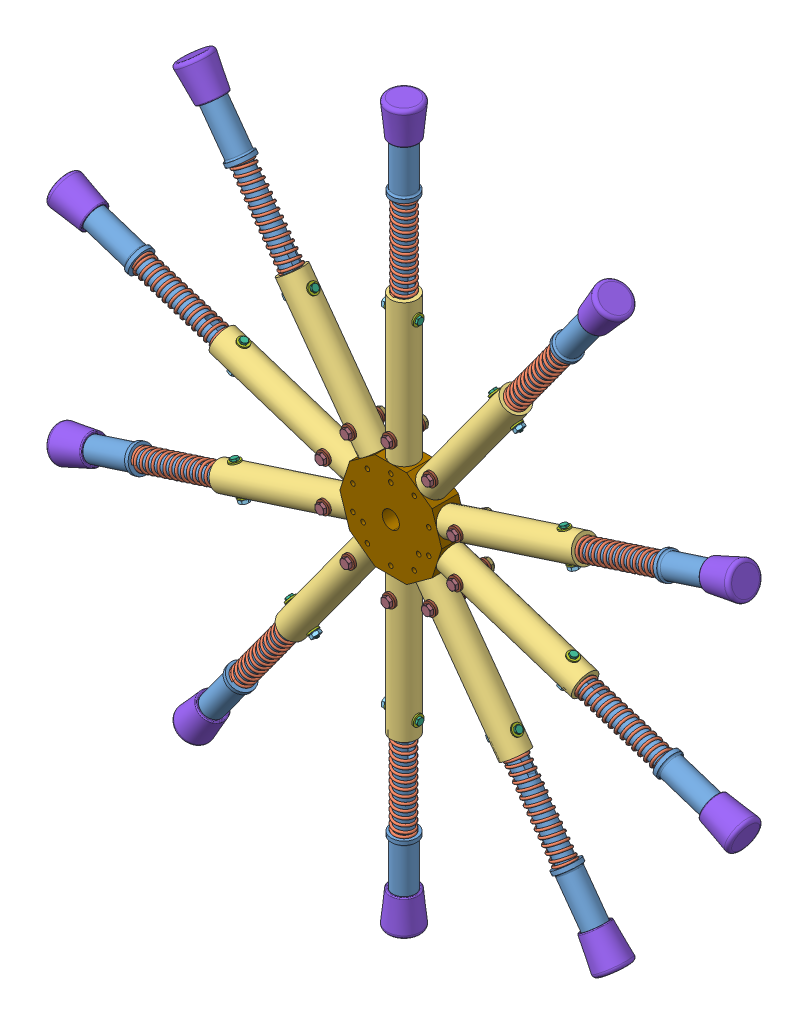
SolidWorks assembly RR2 Rimless Wheel Subassembly, configuration Default. Lengths in mm.
Overall size (516.27 533.18 29.42).
152 component instances, 13 part files, 91 mates.
Components (placement in the parent):
- RR2 Leg Subassembly-1: RR2 Leg Subassembly [Default] at (-53.9197 131.5696 42.2256) x (0 0 1) z (-0.951057 0.309017 0) size (29.42 28.7 230.63)
  - RR2 Leg Rod-1: RR2 Leg Rod [Default] at (-32.4466 0 163.322) x (-1 0 0) z (0 -1 0) size (19.05 163.32 19.05)
  - RR2 Spring-1: RR2 Spring [9657K421] at (-32.6702 -0.1472 114.3) size (17.2 17.2 64.41)
  - RR2 Leg Tube-1: RR2 Leg Tube [Default] at (-32.4466 0 50.8) x (0 -1 0) z (1 0 0) size (19.56 105.41 19.56)
  - RR2 4 Bushing-1: RR2 4 Bushing [94639A664] at (-32.4466 -0.0931 38.1) x (0.887003 0 -0.461764) z (0 1 0) size (4.76 4.76 19.05)
  - RR2 4 Nut-2: RR2 4 Nut [90101A004] at (-32.4466 -13.6074 38.1) x (0.996652 0 0.081761) z (-0.081761 0 0.996652) size (6.35 2.86 7.33)
  - RR2 4 Screw-1: RR2 4 Screw [92314A115] at (-32.4466 10.8477 38.1) x (0.159771 0 0.987154) z (0 1 0) size (4.76 5.5 27.24)
  - RR2 4 Washer-1: RR2 4 Washer [96659A101] at (-32.4466 -10.8293 38.1) x (0.112204 0 0.993685) z (-0.993685 0 0.112204) size (7.92 1.02 7.92)
  - RR2 4 Washer-2: RR2 4 Washer [96659A101] at (-32.4466 9.8317 38.1) x (-0.013346 0 0.999911) z (-0.999911 0 -0.013346) size (7.92 1.02 7.92)
  - RR2 Boot-1: RR2 Boot [Default] at (-32.4466 0 176.022) x (1 0 0) z (0 1 0) size (29.42 25.4 27.68)
- RR2 Leg Subassembly-2: RR2 Leg Subassembly [Default] at (-21.0184 176.8545 42.2256) x (0 0 1) z (-0.587785 0.809017 0) size (29.42 28.7 230.63)
  - RR2 Leg Rod-1: RR2 Leg Rod [Default] at (-32.4466 0 163.322) x (-1 0 0) z (0 -1 0) size (19.05 163.32 19.05)
  - RR2 Spring-1: RR2 Spring [9657K421] at (-32.6702 -0.1472 114.3) size (17.2 17.2 64.41)
  - RR2 Leg Tube-1: RR2 Leg Tube [Default] at (-32.4466 0 50.8) x (0 -1 0) z (1 0 0) size (19.56 105.41 19.56)
  - RR2 4 Bushing-1: RR2 4 Bushing [94639A664] at (-32.4466 -0.0931 38.1) x (0.887003 0 -0.461764) z (0 1 0) size (4.76 4.76 19.05)
  - RR2 4 Nut-2: RR2 4 Nut [90101A004] at (-32.4466 -13.6074 38.1) x (0.996652 0 0.081761) z (-0.081761 0 0.996652) size (6.35 2.86 7.33)
  - RR2 4 Screw-1: RR2 4 Screw [92314A115] at (-32.4466 10.8477 38.1) x (0.159771 0 0.987154) z (0 1 0) size (4.76 5.5 27.24)
  - RR2 4 Washer-1: RR2 4 Washer [96659A101] at (-32.4466 -10.8293 38.1) x (0.112204 0 0.993685) z (-0.993685 0 0.112204) size (7.92 1.02 7.92)
  - RR2 4 Washer-2: RR2 4 Washer [96659A101] at (-32.4466 9.8317 38.1) x (-0.013346 0 0.999911) z (-0.999911 0 -0.013346) size (7.92 1.02 7.92)
  - RR2 Boot-1: RR2 Boot [Default] at (-32.4466 0 176.022) x (1 0 0) z (0 1 0) size (29.42 25.4 27.68)
- RR2 Leg Subassembly-3: RR2 Leg Subassembly [Default] at (-21.0184 30.3097 42.2256) x (0 0 1) z (-0.587785 -0.809017 0) size (29.42 28.7 230.63)
  - RR2 Leg Rod-1: RR2 Leg Rod [Default] at (-32.4466 0 163.322) x (-1 0 0) z (0 -1 0) size (19.05 163.32 19.05)
  - RR2 Spring-1: RR2 Spring [9657K421] at (-32.6702 -0.1472 114.3) size (17.2 17.2 64.41)
  - RR2 Leg Tube-1: RR2 Leg Tube [Default] at (-32.4466 0 50.8) x (0 -1 0) z (1 0 0) size (19.56 105.41 19.56)
  - RR2 4 Bushing-1: RR2 4 Bushing [94639A664] at (-32.4466 -0.0931 38.1) x (0.887003 0 -0.461764) z (0 1 0) size (4.76 4.76 19.05)
  - RR2 4 Nut-2: RR2 4 Nut [90101A004] at (-32.4466 -13.6074 38.1) x (0.996652 0 0.081761) z (-0.081761 0 0.996652) size (6.35 2.86 7.33)
  - RR2 4 Screw-1: RR2 4 Screw [92314A115] at (-32.4466 10.8477 38.1) x (0.159771 0 0.987154) z (0 1 0) size (4.76 5.5 27.24)
  - RR2 4 Washer-1: RR2 4 Washer [96659A101] at (-32.4466 -10.8293 38.1) x (0.112204 0 0.993685) z (-0.993685 0 0.112204) size (7.92 1.02 7.92)
  - RR2 4 Washer-2: RR2 4 Washer [96659A101] at (-32.4466 9.8317 38.1) x (-0.013346 0 0.999911) z (-0.999911 0 -0.013346) size (7.92 1.02 7.92)
  - RR2 Boot-1: RR2 Boot [Default] at (-32.4466 0 176.022) x (1 0 0) z (0 1 0) size (29.42 25.4 27.68)
- RR2 Leg Subassembly-4: RR2 Leg Subassembly [Default] at (-53.9197 75.5945 42.2256) x (0 0 1) z (-0.951057 -0.309017 0) size (29.42 28.7 230.63)
  - RR2 Leg Rod-1: RR2 Leg Rod [Default] at (-32.4466 0 163.322) x (-1 0 0) z (0 -1 0) size (19.05 163.32 19.05)
  - RR2 Spring-1: RR2 Spring [9657K421] at (-32.6702 -0.1472 114.3) size (17.2 17.2 64.41)
  - RR2 Leg Tube-1: RR2 Leg Tube [Default] at (-32.4466 0 50.8) x (0 -1 0) z (1 0 0) size (19.56 105.41 19.56)
  - RR2 4 Bushing-1: RR2 4 Bushing [94639A664] at (-32.4466 -0.0931 38.1) x (0.887003 0 -0.461764) z (0 1 0) size (4.76 4.76 19.05)
  - RR2 4 Nut-2: RR2 4 Nut [90101A004] at (-32.4466 -13.6074 38.1) x (0.996652 0 0.081761) z (-0.081761 0 0.996652) size (6.35 2.86 7.33)
  - RR2 4 Screw-1: RR2 4 Screw [92314A115] at (-32.4466 10.8477 38.1) x (0.159771 0 0.987154) z (0 1 0) size (4.76 5.5 27.24)
  - RR2 4 Washer-1: RR2 4 Washer [96659A101] at (-32.4466 -10.8293 38.1) x (0.112204 0 0.993685) z (-0.993685 0 0.112204) size (7.92 1.02 7.92)
  - RR2 4 Washer-2: RR2 4 Washer [96659A101] at (-32.4466 9.8317 38.1) x (-0.013346 0 0.999911) z (-0.999911 0 -0.013346) size (7.92 1.02 7.92)
  - RR2 Boot-1: RR2 Boot [Default] at (-32.4466 0 176.022) x (1 0 0) z (0 1 0) size (29.42 25.4 27.68)
- RR2 Leg Subassembly-5: RR2 Leg Subassembly [Default] at (32.2171 194.1517 42.2256) x (0 0 1) z (0 1 0) size (29.42 28.7 230.63)
  - RR2 Leg Rod-1: RR2 Leg Rod [Default] at (-32.4466 0 163.322) x (-1 0 0) z (0 -1 0) size (19.05 163.32 19.05)
  - RR2 Spring-1: RR2 Spring [9657K421] at (-32.6702 -0.1472 114.3) size (17.2 17.2 64.41)
  - RR2 Leg Tube-1: RR2 Leg Tube [Default] at (-32.4466 0 50.8) x (0 -1 0) z (1 0 0) size (19.56 105.41 19.56)
  - RR2 4 Bushing-1: RR2 4 Bushing [94639A664] at (-32.4466 -0.0931 38.1) x (0.887003 0 -0.461764) z (0 1 0) size (4.76 4.76 19.05)
  - RR2 4 Nut-2: RR2 4 Nut [90101A004] at (-32.4466 -13.6074 38.1) x (0.996652 0 0.081761) z (-0.081761 0 0.996652) size (6.35 2.86 7.33)
  - RR2 4 Screw-1: RR2 4 Screw [92314A115] at (-32.4466 10.8477 38.1) x (0.159771 0 0.987154) z (0 1 0) size (4.76 5.5 27.24)
  - RR2 4 Washer-1: RR2 4 Washer [96659A101] at (-32.4466 -10.8293 38.1) x (0.112204 0 0.993685) z (-0.993685 0 0.112204) size (7.92 1.02 7.92)
  - RR2 4 Washer-2: RR2 4 Washer [96659A101] at (-32.4466 9.8317 38.1) x (-0.013346 0 0.999911) z (-0.999911 0 -0.013346) size (7.92 1.02 7.92)
  - RR2 Boot-1: RR2 Boot [Default] at (-32.4466 0 176.022) x (1 0 0) z (0 1 0) size (29.42 25.4 27.68)
- RR2 Leg Subassembly-6: RR2 Leg Subassembly [Default] at (85.4526 176.8545 -22.6676) x (0 0 -1) z (0.587785 0.809017 0) size (29.42 28.7 230.63)
  - RR2 Leg Rod-1: RR2 Leg Rod [Default] at (-32.4466 0 163.322) x (-1 0 0) z (0 -1 0) size (19.05 163.32 19.05)
  - RR2 Spring-1: RR2 Spring [9657K421] at (-32.6702 -0.1472 114.3) size (17.2 17.2 64.41)
  - RR2 Leg Tube-1: RR2 Leg Tube [Default] at (-32.4466 0 50.8) x (0 -1 0) z (1 0 0) size (19.56 105.41 19.56)
  - RR2 4 Bushing-1: RR2 4 Bushing [94639A664] at (-32.4466 -0.0931 38.1) x (0.887003 0 -0.461764) z (0 1 0) size (4.76 4.76 19.05)
  - RR2 4 Nut-2: RR2 4 Nut [90101A004] at (-32.4466 -13.6074 38.1) x (0.996652 0 0.081761) z (-0.081761 0 0.996652) size (6.35 2.86 7.33)
  - RR2 4 Screw-1: RR2 4 Screw [92314A115] at (-32.4466 10.8477 38.1) x (0.159771 0 0.987154) z (0 1 0) size (4.76 5.5 27.24)
  - RR2 4 Washer-1: RR2 4 Washer [96659A101] at (-32.4466 -10.8293 38.1) x (0.112204 0 0.993685) z (-0.993685 0 0.112204) size (7.92 1.02 7.92)
  - RR2 4 Washer-2: RR2 4 Washer [96659A101] at (-32.4466 9.8317 38.1) x (-0.013346 0 0.999911) z (-0.999911 0 -0.013346) size (7.92 1.02 7.92)
  - RR2 Boot-1: RR2 Boot [Default] at (-32.4466 0 176.022) x (1 0 0) z (0 1 0) size (29.42 25.4 27.68)
- RR2 Leg Subassembly-7: RR2 Leg Subassembly [Default] at (118.354 131.5696 -22.6676) x (0 0 -1) z (0.951057 0.309017 0) size (29.42 28.7 230.63)
  - RR2 Leg Rod-1: RR2 Leg Rod [Default] at (-32.4466 0 163.322) x (-1 0 0) z (0 -1 0) size (19.05 163.32 19.05)
  - RR2 Spring-1: RR2 Spring [9657K421] at (-32.6702 -0.1472 114.3) size (17.2 17.2 64.41)
  - RR2 Leg Tube-1: RR2 Leg Tube [Default] at (-32.4466 0 50.8) x (0 -1 0) z (1 0 0) size (19.56 105.41 19.56)
  - RR2 4 Bushing-1: RR2 4 Bushing [94639A664] at (-32.4466 -0.0931 38.1) x (0.887003 0 -0.461764) z (0 1 0) size (4.76 4.76 19.05)
  - RR2 4 Nut-2: RR2 4 Nut [90101A004] at (-32.4466 -13.6074 38.1) x (0.996652 0 0.081761) z (-0.081761 0 0.996652) size (6.35 2.86 7.33)
  - RR2 4 Screw-1: RR2 4 Screw [92314A115] at (-32.4466 10.8477 38.1) x (0.159771 0 0.987154) z (0 1 0) size (4.76 5.5 27.24)
  - RR2 4 Washer-1: RR2 4 Washer [96659A101] at (-32.4466 -10.8293 38.1) x (0.112204 0 0.993685) z (-0.993685 0 0.112204) size (7.92 1.02 7.92)
  - RR2 4 Washer-2: RR2 4 Washer [96659A101] at (-32.4466 9.8317 38.1) x (-0.013346 0 0.999911) z (-0.999911 0 -0.013346) size (7.92 1.02 7.92)
  - RR2 Boot-1: RR2 Boot [Default] at (-32.4466 0 176.022) x (1 0 0) z (0 1 0) size (29.42 25.4 27.68)
- RR2 Leg Subassembly-8: RR2 Leg Subassembly [Default] at (118.354 75.5945 -22.6676) x (0 0 -1) z (0.951057 -0.309017 0) size (29.42 28.7 230.63)
  - RR2 Leg Rod-1: RR2 Leg Rod [Default] at (-32.4466 0 163.322) x (-1 0 0) z (0 -1 0) size (19.05 163.32 19.05)
  - RR2 Spring-1: RR2 Spring [9657K421] at (-32.6702 -0.1472 114.3) size (17.2 17.2 64.41)
  - RR2 Leg Tube-1: RR2 Leg Tube [Default] at (-32.4466 0 50.8) x (0 -1 0) z (1 0 0) size (19.56 105.41 19.56)
  - RR2 4 Bushing-1: RR2 4 Bushing [94639A664] at (-32.4466 -0.0931 38.1) x (0.887003 0 -0.461764) z (0 1 0) size (4.76 4.76 19.05)
  - RR2 4 Nut-2: RR2 4 Nut [90101A004] at (-32.4466 -13.6074 38.1) x (0.996652 0 0.081761) z (-0.081761 0 0.996652) size (6.35 2.86 7.33)
  - RR2 4 Screw-1: RR2 4 Screw [92314A115] at (-32.4466 10.8477 38.1) x (0.159771 0 0.987154) z (0 1 0) size (4.76 5.5 27.24)
  - RR2 4 Washer-1: RR2 4 Washer [96659A101] at (-32.4466 -10.8293 38.1) x (0.112204 0 0.993685) z (-0.993685 0 0.112204) size (7.92 1.02 7.92)
  - RR2 4 Washer-2: RR2 4 Washer [96659A101] at (-32.4466 9.8317 38.1) x (-0.013346 0 0.999911) z (-0.999911 0 -0.013346) size (7.92 1.02 7.92)
  - RR2 Boot-1: RR2 Boot [Default] at (-32.4466 0 176.022) x (1 0 0) z (0 1 0) size (29.42 25.4 27.68)
- RR2 Leg Subassembly-9: RR2 Leg Subassembly [Default] at (85.4526 30.3097 -22.6676) x (0 0 -1) z (0.587785 -0.809017 0) size (29.42 28.7 230.63)
  - RR2 Leg Rod-1: RR2 Leg Rod [Default] at (-32.4466 0 163.322) x (-1 0 0) z (0 -1 0) size (19.05 163.32 19.05)
  - RR2 Spring-1: RR2 Spring [9657K421] at (-32.6702 -0.1472 114.3) size (17.2 17.2 64.41)
  - RR2 Leg Tube-1: RR2 Leg Tube [Default] at (-32.4466 0 50.8) x (0 -1 0) z (1 0 0) size (19.56 105.41 19.56)
  - RR2 4 Bushing-1: RR2 4 Bushing [94639A664] at (-32.4466 -0.0931 38.1) x (0.887003 0 -0.461764) z (0 1 0) size (4.76 4.76 19.05)
  - RR2 4 Nut-2: RR2 4 Nut [90101A004] at (-32.4466 -13.6074 38.1) x (0.996652 0 0.081761) z (-0.081761 0 0.996652) size (6.35 2.86 7.33)
  - RR2 4 Screw-1: RR2 4 Screw [92314A115] at (-32.4466 10.8477 38.1) x (0.159771 0 0.987154) z (0 1 0) size (4.76 5.5 27.24)
  - RR2 4 Washer-1: RR2 4 Washer [96659A101] at (-32.4466 -10.8293 38.1) x (0.112204 0 0.993685) z (-0.993685 0 0.112204) size (7.92 1.02 7.92)
  - RR2 4 Washer-2: RR2 4 Washer [96659A101] at (-32.4466 9.8317 38.1) x (-0.013346 0 0.999911) z (-0.999911 0 -0.013346) size (7.92 1.02 7.92)
  - RR2 Boot-1: RR2 Boot [Default] at (-32.4466 0 176.022) x (1 0 0) z (0 1 0) size (29.42 25.4 27.68)
- RR2 Hub Subassembly-1: RR2 Hub Subassembly [Default] at (22.7483 69.4036 0) size (125.44 128.31 19.56)
  - RR2 Hub Rev B-1: RR2 Hub Rev B [Default] at (9.4688 34.1785 19.558) size (75.62 71.92 19.56)
  - RR2 Peg-1: RR2 Peg [Default] at (23.1405 52.9959 9.779) x (0.809017 -0.587785 0) z (0 0 1) size (11.05 40.89 11.05)
  - RR2 Peg-2: RR2 Peg [Default] at (9.4688 57.4381 9.779) x (-1 0 0) z (0 0 -1) size (11.05 40.89 11.05)
  - RR2 Peg-3: RR2 Peg [Default] at (31.5901 26.9908 9.779) x (-0.309017 -0.951057 0) z (0 0 1) size (11.05 40.89 11.05)
  - RR2 Peg-4: RR2 Peg [Default] at (31.5901 41.3661 9.779) x (0.309017 -0.951057 0) z (0 0 1) size (11.05 40.89 11.05)
  - RR2 Peg-5: RR2 Peg [Default] at (-4.2028 52.9959 9.779) x (0.809017 0.587785 0) z (0 0 1) size (11.05 40.89 11.05)
  - RR2 Peg-6: RR2 Peg [Default] at (-12.6524 26.9908 9.779) x (-0.309017 0.951057 0) z (0 0 1) size (11.05 40.89 11.05)
  - RR2 Peg-7: RR2 Peg [Default] at (-12.6524 41.3661 9.779) x (-0.309017 -0.951057 0) z (0 0 -1) size (11.05 40.89 11.05)
  - RR2 Peg-8: RR2 Peg [Default] at (-4.2028 15.361 9.779) x (-0.809017 0.587785 0) z (0 0 1) size (11.05 40.89 11.05)
  - RR2 Peg-9: RR2 Peg [Default] at (9.4688 10.9188 9.779) x (-1 0 0) z (0 0 1) size (11.05 40.89 11.05)
  - RR2 Peg-10: RR2 Peg [Default] at (23.1405 15.361 9.779) x (0.809017 0.587785 0) z (0 0 -1) size (11.05 40.89 11.05)
- RR2 Leg Subassembly-11: RR2 Leg Subassembly [Default] at (32.2171 13.0124 -22.6676) x (0 0 -1) z (0 -1 0) size (29.42 28.7 230.63)
  - RR2 Leg Rod-1: RR2 Leg Rod [Default] at (-32.4466 0 163.322) x (-1 0 0) z (0 -1 0) size (19.05 163.32 19.05)
  - RR2 Spring-1: RR2 Spring [9657K421] at (-32.6702 -0.1472 114.3) size (17.2 17.2 64.41)
  - RR2 Leg Tube-1: RR2 Leg Tube [Default] at (-32.4466 0 50.8) x (0 -1 0) z (1 0 0) size (19.56 105.41 19.56)
  - RR2 4 Bushing-1: RR2 4 Bushing [94639A664] at (-32.4466 -0.0931 38.1) x (0.887003 0 -0.461764) z (0 1 0) size (4.76 4.76 19.05)
  - RR2 4 Nut-2: RR2 4 Nut [90101A004] at (-32.4466 -13.6074 38.1) x (0.996652 0 0.081761) z (-0.081761 0 0.996652) size (6.35 2.86 7.33)
  - RR2 4 Screw-1: RR2 4 Screw [92314A115] at (-32.4466 10.8477 38.1) x (0.159771 0 0.987154) z (0 1 0) size (4.76 5.5 27.24)
  - RR2 4 Washer-1: RR2 4 Washer [96659A101] at (-32.4466 -10.8293 38.1) x (0.112204 0 0.993685) z (-0.993685 0 0.112204) size (7.92 1.02 7.92)
  - RR2 4 Washer-2: RR2 4 Washer [96659A101] at (-32.4466 9.8317 38.1) x (-0.013346 0 0.999911) z (-0.999911 0 -0.013346) size (7.92 1.02 7.92)
  - RR2 Boot-1: RR2 Boot [Default] at (-32.4466 0 176.022) x (1 0 0) z (0 1 0) size (29.42 25.4 27.68)
- RR2 6 Washer-1: RR2 6 Washer [96659A102] at (32.2171 155.0357 19.558) x (1 0 0) z (0 -1 0) size (9.53 1.65 9.53)
- RR2 6 Washer-2: RR2 6 Washer [96659A102] at (32.2171 155.0357 -1.651) x (1 0 0) z (0 -1 0) size (9.53 1.65 9.53)
- RR2 6 Washer-3: RR2 6 Washer [96659A102] at (62.4608 145.2089 21.209) x (1 0 0) z (0 1 0) size (9.53 1.65 9.53)
- RR2 6 Washer-4: RR2 6 Washer [96659A102] at (62.4608 145.2089 -1.651) x (1 0 0) z (0 -1 0) size (9.53 1.65 9.53)
- RR2 6 Washer-5: RR2 6 Washer [96659A102] at (81.1525 119.4821 21.209) x (1 0 0) z (0 1 0) size (9.53 1.65 9.53)
- RR2 6 Washer-6: RR2 6 Washer [96659A102] at (81.1525 119.4821 -1.651) x (1 0 0) z (0 -1 0) size (9.53 1.65 9.53)
- RR2 6 Washer-7: RR2 6 Washer [96659A102] at (81.1525 87.682 21.209) x (1 0 0) z (0 1 0) size (9.53 1.65 9.53)
- RR2 6 Washer-8: RR2 6 Washer [96659A102] at (81.1525 87.682 -1.651) x (1 0 0) z (0 -1 0) size (9.53 1.65 9.53)
- RR2 6 Washer-9: RR2 6 Washer [96659A102] at (62.4608 61.9552 21.209) x (1 0 0) z (0 1 0) size (9.53 1.65 9.53)
- RR2 6 Washer-10: RR2 6 Washer [96659A102] at (62.4608 61.9552 -1.651) x (1 0 0) z (0 -1 0) size (9.53 1.65 9.53)
- RR2 6 Washer-11: RR2 6 Washer [96659A102] at (32.2171 52.1284 21.209) x (1 0 0) z (0 1 0) size (9.53 1.65 9.53)
- RR2 6 Washer-12: RR2 6 Washer [96659A102] at (32.2171 52.1284 -1.651) x (1 0 0) z (0 -1 0) size (9.53 1.65 9.53)
- RR2 6 Washer-13: RR2 6 Washer [96659A102] at (1.9734 61.9552 21.209) x (1 0 0) z (0 1 0) size (9.53 1.65 9.53)
- RR2 6 Washer-14: RR2 6 Washer [96659A102] at (1.9734 61.9552 -1.651) x (1 0 0) z (0 -1 0) size (9.53 1.65 9.53)
- RR2 6 Washer-15: RR2 6 Washer [96659A102] at (-16.7182 87.682 21.209) x (1 0 0) z (0 1 0) size (9.53 1.65 9.53)
- RR2 6 Washer-16: RR2 6 Washer [96659A102] at (-16.7182 87.682 -1.651) x (1 0 0) z (0 -1 0) size (9.53 1.65 9.53)
- RR2 6 Washer-17: RR2 6 Washer [96659A102] at (-16.7182 119.4821 21.209) x (1 0 0) z (0 1 0) size (9.53 1.65 9.53)
- RR2 6 Washer-18: RR2 6 Washer [96659A102] at (-16.7182 119.4821 -1.651) x (1 0 0) z (0 -1 0) size (9.53 1.65 9.53)
- RR2 6 Washer-19: RR2 6 Washer [96659A102] at (1.9734 145.2089 21.209) x (1 0 0) z (0 1 0) size (9.53 1.65 9.53)
- RR2 6 Washer-20: RR2 6 Washer [96659A102] at (1.9734 145.2089 -1.651) x (1 0 0) z (0 -1 0) size (9.53 1.65 9.53)
- RR2 6 Nut-1: RR2 6 Nut [90101A007] at (32.2171 155.0357 -1.651) x (1 0 0) z (0 1 0) size (7.94 3.28 9.17)
- RR2 6 Nut-2: RR2 6 Nut [90101A007] at (62.4608 145.2089 -1.651) x (1 0 0) z (0 1 0) size (7.94 3.28 9.17)
- RR2 6 Nut-3: RR2 6 Nut [90101A007] at (81.1525 119.4821 -1.651) x (1 0 0) z (0 1 0) size (7.94 3.28 9.17)
- RR2 6 Nut-4: RR2 6 Nut [90101A007] at (81.1525 87.682 -1.651) x (1 0 0) z (0 1 0) size (7.94 3.28 9.17)
- RR2 6 Nut-5: RR2 6 Nut [90101A007] at (62.4608 61.9552 -1.651) x (1 0 0) z (0 1 0) size (7.94 3.28 9.17)
- RR2 6 Nut-6: RR2 6 Nut [90101A007] at (32.2171 52.1284 -1.651) x (1 0 0) z (0 1 0) size (7.94 3.28 9.17)
- RR2 6 Nut-7: RR2 6 Nut [90101A007] at (1.9734 61.9552 -1.651) x (1 0 0) z (0 1 0) size (7.94 3.28 9.17)
- RR2 6 Nut-8: RR2 6 Nut [90101A007] at (-16.7182 87.682 -1.651) x (1 0 0) z (0 1 0) size (7.94 3.28 9.17)
- RR2 6 Nut-9: RR2 6 Nut [90101A007] at (-16.7182 119.4821 -1.651) x (1 0 0) z (0 1 0) size (7.94 3.28 9.17)
- RR2 6 Nut-10: RR2 6 Nut [90101A007] at (1.9734 145.2089 -1.651) x (1 0 0) z (0 1 0) size (7.94 3.28 9.17)
- RR2 6 Screw-1: RR2 6 Screw [92314A153] at (32.2171 155.0357 21.4758) size (6.35 7.33 28.12)
- RR2 6 Screw-2: RR2 6 Screw [92314A153] at (62.4608 145.2089 21.4758) size (6.35 7.33 28.12)
- RR2 6 Screw-3: RR2 6 Screw [92314A153] at (81.1525 119.4821 21.4758) size (6.35 7.33 28.12)
- RR2 6 Screw-4: RR2 6 Screw [92314A153] at (81.1525 87.682 21.4758) size (6.35 7.33 28.12)
- RR2 6 Screw-5: RR2 6 Screw [92314A153] at (62.4608 61.9552 21.4758) size (6.35 7.33 28.12)
- RR2 6 Screw-6: RR2 6 Screw [92314A153] at (32.2171 52.1284 21.4758) size (6.35 7.33 28.12)
- RR2 6 Screw-7: RR2 6 Screw [92314A153] at (1.9734 61.9552 21.4758) size (6.35 7.33 28.12)
- RR2 6 Screw-8: RR2 6 Screw [92314A153] at (-16.7182 87.682 21.4758) size (6.35 7.33 28.12)
- RR2 6 Screw-9: RR2 6 Screw [92314A153] at (-16.7182 119.4821 21.4758) size (6.35 7.33 28.12)
- RR2 6 Screw-10: RR2 6 Screw [92314A153] at (1.9734 145.2089 21.4758) size (6.35 7.33 28.12)
Mates (geometry in assembly coordinates):
- Coincident1: coincident anti-aligned: plane of RR2 Hub Subassembly-1/RR2 Hub Rev B-1 through (32.2171 103.5821 0) normal (0 0 -1); plane of assembly through (0 0 0) normal (0 0 1)
- Concentric1: concentric anti-aligned: cylinder of RR2 Leg Subassembly-5/RR2 Leg Tube-1 through (32.2171 139.5417 9.779) axis (0 1 0) radius 5.7785; cylinder of RR2 Hub Subassembly-1/RR2 Peg-2 through (32.2171 167.7357 9.779) axis (0 -1 0) radius 5.5245
- Concentric2: concentric anti-aligned: cylinder of RR2 Leg Subassembly-2/RR2 Leg Tube-1 through (11.0806 132.674 9.779) axis (-0.587785 0.809017 0) radius 5.7785; cylinder of RR2 Hub Subassembly-1/RR2 Peg-5 through (-5.4914 155.4835 9.779) axis (0.587785 -0.809017 0) radius 5.5245
- Concentric3: concentric anti-aligned: cylinder of RR2 Leg Subassembly-1/RR2 Leg Tube-1 through (-1.9825 114.6942 9.779) axis (-0.951057 0.309017 0) radius 5.7785; cylinder of RR2 Hub Subassembly-1/RR2 Peg-7 through (-28.7966 123.4066 9.779) axis (0.951057 -0.309017 0) radius 5.5245
- Concentric4: concentric anti-aligned: cylinder of RR2 Leg Subassembly-4/RR2 Leg Tube-1 through (-1.9825 92.4699 9.779) axis (-0.951057 -0.309017 0) radius 5.7785; cylinder of RR2 Hub Subassembly-1/RR2 Peg-6 through (-28.7966 83.7575 9.779) axis (0.951057 0.309017 0) radius 5.5245
- Concentric5: concentric anti-aligned: cylinder of RR2 Leg Subassembly-3/RR2 Leg Tube-1 through (11.0806 74.4901 9.779) axis (-0.587785 -0.809017 0) radius 5.7785; cylinder of RR2 Hub Subassembly-1/RR2 Peg-8 through (-5.4914 51.6807 9.779) axis (0.587785 0.809017 0) radius 5.5245
- Concentric6: concentric anti-aligned: cylinder of RR2 Hub Subassembly-1/RR2 Peg-9 through (32.2171 39.4284 9.779) axis (0 1 0) radius 5.5245; cylinder of RR2 Leg Subassembly-11/RR2 Leg Tube-1 through (32.2171 67.6224 9.779) axis (0 -1 0) radius 5.7785
- Concentric7: concentric anti-aligned: cylinder of RR2 Leg Subassembly-9/RR2 Leg Tube-1 through (53.3537 74.4901 9.779) axis (0.587785 -0.809017 0) radius 5.7785; cylinder of RR2 Hub Subassembly-1/RR2 Peg-10 through (69.9257 51.6807 9.779) axis (-0.587785 0.809017 0) radius 5.5245
- Concentric8: concentric anti-aligned: cylinder of RR2 Leg Subassembly-8/RR2 Leg Tube-1 through (66.4168 92.4699 9.779) axis (0.951057 -0.309017 0) radius 5.7785; cylinder of RR2 Hub Subassembly-1/RR2 Peg-3 through (93.2309 83.7575 9.779) axis (-0.951057 0.309017 0) radius 5.5245
- Concentric9: concentric anti-aligned: cylinder of RR2 Leg Subassembly-7/RR2 Leg Tube-1 through (66.4168 114.6942 9.779) axis (0.951057 0.309017 0) radius 5.7785; cylinder of RR2 Hub Subassembly-1/RR2 Peg-4 through (93.2309 123.4066 9.779) axis (-0.951057 -0.309017 0) radius 5.5245
- Concentric10: concentric anti-aligned: cylinder of RR2 Leg Subassembly-6/RR2 Leg Tube-1 through (53.3537 132.674 9.779) axis (0.587785 0.809017 0) radius 5.7785; cylinder of RR2 Hub Subassembly-1/RR2 Peg-1 through (69.9257 155.4835 9.779) axis (-0.587785 -0.809017 0) radius 5.5245
- Concentric11: concentric anti-aligned: cylinder of RR2 Leg Subassembly-5/RR2 Leg Tube-1 through (32.2171 155.0357 0) axis (0 0 1) radius 1.905; cylinder of RR2 Hub Subassembly-1/RR2 Peg-2 through (32.2171 155.0357 15.3035) axis (0 0 -1) radius 1.905
- Concentric13: concentric aligned: cylinder of RR2 Leg Subassembly-2/RR2 Leg Tube-1 through (1.9734 145.2089 0) axis (0 0 1) radius 1.905; cylinder of RR2 Hub Subassembly-1/RR2 Peg-5 through (1.9734 145.2089 4.2545) axis (0 0 1) radius 1.905
- Concentric14: concentric anti-aligned: cylinder of RR2 Leg Subassembly-1/RR2 Leg Tube-1 through (-16.7182 119.4821 0) axis (0 0 1) radius 1.905; cylinder of RR2 Hub Subassembly-1/RR2 Peg-7 through (-16.7182 119.4821 15.3035) axis (0 0 -1) radius 1.905
- Concentric15: concentric aligned: cylinder of RR2 Leg Subassembly-4/RR2 Leg Tube-1 through (-16.7182 87.682 0) axis (0 0 1) radius 1.905; cylinder of RR2 Hub Subassembly-1/RR2 Peg-6 through (-16.7182 87.682 4.2545) axis (0 0 1) radius 1.905
- Concentric17: concentric aligned: cylinder of RR2 Leg Subassembly-3/RR2 Leg Tube-1 through (1.9734 61.9552 0) axis (0 0 1) radius 1.905; cylinder of RR2 Hub Subassembly-1/RR2 Peg-8 through (1.9734 61.9552 4.2545) axis (0 0 1) radius 1.905
- Concentric19: concentric anti-aligned: cylinder of RR2 Hub Subassembly-1/RR2 Peg-9 through (32.2171 52.1284 4.2545) axis (0 0 1) radius 1.905; cylinder of RR2 Leg Subassembly-11/RR2 Leg Tube-1 through (32.2171 52.1284 19.558) axis (0 0 -1) radius 1.905
- Concentric21: concentric aligned: cylinder of RR2 Leg Subassembly-9/RR2 Leg Tube-1 through (62.4608 61.9552 19.558) axis (0 0 -1) radius 1.905; cylinder of RR2 Hub Subassembly-1/RR2 Peg-10 through (62.4608 61.9552 15.3035) axis (0 0 -1) radius 1.905
- Concentric23: concentric anti-aligned: cylinder of RR2 Leg Subassembly-8/RR2 Leg Tube-1 through (81.1525 87.682 19.558) axis (0 0 -1) radius 1.905; cylinder of RR2 Hub Subassembly-1/RR2 Peg-3 through (81.1525 87.682 4.2545) axis (0 0 1) radius 1.905
- Concentric25: concentric anti-aligned: cylinder of RR2 Leg Subassembly-7/RR2 Leg Tube-1 through (81.1525 119.4821 19.558) axis (0 0 -1) radius 1.905; cylinder of RR2 Hub Subassembly-1/RR2 Peg-4 through (81.1525 119.4821 4.2545) axis (0 0 1) radius 1.905
- Concentric27: concentric anti-aligned: cylinder of RR2 Leg Subassembly-6/RR2 Leg Tube-1 through (62.4608 145.2089 19.558) axis (0 0 -1) radius 1.905; cylinder of RR2 Hub Subassembly-1/RR2 Peg-1 through (62.4608 145.2089 4.2545) axis (0 0 1) radius 1.905
- Concentric28: concentric anti-aligned: cylinder of RR2 Hub Subassembly-1/RR2 Peg-2 through (32.2171 155.0357 15.3035) axis (0 0 -1) radius 1.905; cylinder of RR2 6 Washer-1 through (32.2171 155.0357 19.558) axis (0 0 1) radius 1.9812
- Coincident2: coincident anti-aligned: plane of RR2 Hub Subassembly-1/RR2 Hub Rev B-1 through (32.2171 103.5821 19.558) normal (0 0 1); plane of RR2 6 Washer-1 through (32.2171 155.0357 19.558) normal (0 0 -1)
- Coincident3: coincident anti-aligned: plane of RR2 Hub Subassembly-1/RR2 Hub Rev B-1 through (32.2171 103.5821 19.558) normal (0 0 1); plane of RR2 6 Washer-3 through (62.4608 145.2089 19.558) normal (0 0 -1)
- Concentric29: concentric aligned: cylinder of RR2 Leg Subassembly-6/RR2 Leg Tube-1 through (62.4608 145.2089 19.558) axis (0 0 -1) radius 1.905; cylinder of RR2 6 Washer-3 through (62.4608 145.2089 21.209) axis (0 0 -1) radius 1.9812
- Coincident4: coincident anti-aligned: plane of RR2 Hub Subassembly-1/RR2 Hub Rev B-1 through (32.2171 103.5821 19.558) normal (0 0 1); plane of RR2 6 Washer-5 through (81.1525 119.4821 19.558) normal (0 0 -1)
- Concentric30: concentric aligned: cylinder of RR2 Leg Subassembly-7/RR2 Leg Tube-1 through (81.1525 119.4821 19.558) axis (0 0 -1) radius 1.905; cylinder of RR2 6 Washer-5 through (81.1525 119.4821 21.209) axis (0 0 -1) radius 1.9812
- Coincident5: coincident anti-aligned: plane of RR2 Hub Subassembly-1/RR2 Hub Rev B-1 through (32.2171 103.5821 19.558) normal (0 0 1); plane of RR2 6 Washer-7 through (81.1525 87.682 19.558) normal (0 0 -1)
- Concentric31: concentric aligned: cylinder of RR2 Leg Subassembly-8/RR2 Leg Tube-1 through (81.1525 87.682 19.558) axis (0 0 -1) radius 1.905; cylinder of RR2 6 Washer-7 through (81.1525 87.682 21.209) axis (0 0 -1) radius 1.9812
- Coincident6: coincident anti-aligned: plane of RR2 Hub Subassembly-1/RR2 Hub Rev B-1 through (32.2171 103.5821 19.558) normal (0 0 1); plane of RR2 6 Washer-9 through (62.4608 61.9552 19.558) normal (0 0 -1)
- Concentric32: concentric aligned: cylinder of RR2 Leg Subassembly-9/RR2 Leg Tube-1 through (62.4608 61.9552 19.558) axis (0 0 -1) radius 1.905; cylinder of RR2 6 Washer-9 through (62.4608 61.9552 21.209) axis (0 0 -1) radius 1.9812
- Coincident7: coincident anti-aligned: plane of RR2 Hub Subassembly-1/RR2 Hub Rev B-1 through (32.2171 103.5821 19.558) normal (0 0 1); plane of RR2 6 Washer-11 through (32.2171 52.1284 19.558) normal (0 0 -1)
- Concentric33: concentric aligned: cylinder of RR2 Leg Subassembly-11/RR2 Leg Tube-1 through (32.2171 52.1284 19.558) axis (0 0 -1) radius 1.905; cylinder of RR2 6 Washer-11 through (32.2171 52.1284 21.209) axis (0 0 -1) radius 1.9812
- Coincident8: coincident anti-aligned: plane of RR2 Hub Subassembly-1/RR2 Hub Rev B-1 through (32.2171 103.5821 19.558) normal (0 0 1); plane of RR2 6 Washer-13 through (1.9734 61.9552 19.558) normal (0 0 -1)
- Concentric34: concentric anti-aligned: cylinder of RR2 Leg Subassembly-3/RR2 Leg Tube-1 through (1.9734 61.9552 0) axis (0 0 1) radius 1.905; cylinder of RR2 6 Washer-13 through (1.9734 61.9552 21.209) axis (0 0 -1) radius 1.9812
- Coincident9: coincident anti-aligned: plane of RR2 Hub Subassembly-1/RR2 Hub Rev B-1 through (32.2171 103.5821 19.558) normal (0 0 1); plane of RR2 6 Washer-15 through (-16.7182 87.682 19.558) normal (0 0 -1)
- Concentric35: concentric anti-aligned: cylinder of RR2 Leg Subassembly-4/RR2 Leg Tube-1 through (-16.7182 87.682 0) axis (0 0 1) radius 1.905; cylinder of RR2 6 Washer-15 through (-16.7182 87.682 21.209) axis (0 0 -1) radius 1.9812
- Coincident10: coincident anti-aligned: plane of RR2 Hub Subassembly-1/RR2 Hub Rev B-1 through (32.2171 103.5821 19.558) normal (0 0 1); plane of RR2 6 Washer-17 through (-16.7182 119.4821 19.558) normal (0 0 -1)
- Concentric36: concentric anti-aligned: cylinder of RR2 Leg Subassembly-1/RR2 Leg Tube-1 through (-16.7182 119.4821 0) axis (0 0 1) radius 1.905; cylinder of RR2 6 Washer-17 through (-16.7182 119.4821 21.209) axis (0 0 -1) radius 1.9812
- Coincident11: coincident anti-aligned: plane of RR2 Hub Subassembly-1/RR2 Hub Rev B-1 through (32.2171 103.5821 19.558) normal (0 0 1); plane of RR2 6 Washer-19 through (1.9734 145.2089 19.558) normal (0 0 -1)
- Concentric37: concentric anti-aligned: cylinder of RR2 Leg Subassembly-2/RR2 Leg Tube-1 through (1.9734 145.2089 0) axis (0 0 1) radius 1.905; cylinder of RR2 6 Washer-19 through (1.9734 145.2089 21.209) axis (0 0 -1) radius 1.9812
- Coincident12: coincident anti-aligned: plane of RR2 Hub Subassembly-1/RR2 Hub Rev B-1 through (32.2171 103.5821 0) normal (0 0 -1); plane of RR2 6 Washer-2 through (32.2171 155.0357 0) normal (0 0 1)
- Concentric38: concentric aligned: cylinder of RR2 Leg Subassembly-5/RR2 Leg Tube-1 through (32.2171 155.0357 0) axis (0 0 1) radius 1.905; cylinder of RR2 6 Washer-2 through (32.2171 155.0357 -1.651) axis (0 0 1) radius 1.9812
- Coincident13: coincident anti-aligned: plane of RR2 Hub Subassembly-1/RR2 Hub Rev B-1 through (32.2171 103.5821 0) normal (0 0 -1); plane of RR2 6 Washer-4 through (62.4608 145.2089 0) normal (0 0 1)
- Concentric39: concentric anti-aligned: cylinder of RR2 Leg Subassembly-6/RR2 Leg Tube-1 through (62.4608 145.2089 19.558) axis (0 0 -1) radius 1.905; cylinder of RR2 6 Washer-4 through (62.4608 145.2089 -1.651) axis (0 0 1) radius 1.9812
- Coincident14: coincident anti-aligned: plane of RR2 Hub Subassembly-1/RR2 Hub Rev B-1 through (32.2171 103.5821 0) normal (0 0 -1); plane of RR2 6 Washer-6 through (81.1525 119.4821 0) normal (0 0 1)
- Concentric40: concentric anti-aligned: cylinder of RR2 Leg Subassembly-7/RR2 Leg Tube-1 through (81.1525 119.4821 19.558) axis (0 0 -1) radius 1.905; cylinder of RR2 6 Washer-6 through (81.1525 119.4821 -1.651) axis (0 0 1) radius 1.9812
- Coincident15: coincident anti-aligned: plane of RR2 Hub Subassembly-1/RR2 Hub Rev B-1 through (32.2171 103.5821 0) normal (0 0 -1); plane of RR2 6 Washer-8 through (81.1525 87.682 0) normal (0 0 1)
- Concentric41: concentric anti-aligned: cylinder of RR2 Leg Subassembly-8/RR2 Leg Tube-1 through (81.1525 87.682 19.558) axis (0 0 -1) radius 1.905; cylinder of RR2 6 Washer-8 through (81.1525 87.682 -1.651) axis (0 0 1) radius 1.9812
- Coincident16: coincident anti-aligned: plane of RR2 Hub Subassembly-1/RR2 Hub Rev B-1 through (32.2171 103.5821 0) normal (0 0 -1); plane of RR2 6 Washer-10 through (62.4608 61.9552 0) normal (0 0 1)
- Concentric42: concentric anti-aligned: cylinder of RR2 Leg Subassembly-9/RR2 Leg Tube-1 through (62.4608 61.9552 19.558) axis (0 0 -1) radius 1.905; cylinder of RR2 6 Washer-10 through (62.4608 61.9552 -1.651) axis (0 0 1) radius 1.9812
- Coincident17: coincident anti-aligned: plane of RR2 Hub Subassembly-1/RR2 Hub Rev B-1 through (32.2171 103.5821 0) normal (0 0 -1); plane of RR2 6 Washer-12 through (32.2171 52.1284 0) normal (0 0 1)
- Concentric43: concentric aligned: cylinder of RR2 Hub Subassembly-1/RR2 Peg-9 through (32.2171 52.1284 4.2545) axis (0 0 1) radius 1.905; cylinder of RR2 6 Washer-12 through (32.2171 52.1284 -1.651) axis (0 0 1) radius 1.9812
- Coincident18: coincident anti-aligned: plane of RR2 Hub Subassembly-1/RR2 Hub Rev B-1 through (32.2171 103.5821 0) normal (0 0 -1); plane of RR2 6 Washer-14 through (1.9734 61.9552 0) normal (0 0 1)
- Concentric44: concentric aligned: cylinder of RR2 Leg Subassembly-3/RR2 Leg Tube-1 through (1.9734 61.9552 0) axis (0 0 1) radius 1.905; cylinder of RR2 6 Washer-14 through (1.9734 61.9552 -1.651) axis (0 0 1) radius 1.9812
- Coincident19: coincident anti-aligned: plane of RR2 Hub Subassembly-1/RR2 Hub Rev B-1 through (32.2171 103.5821 0) normal (0 0 -1); plane of RR2 6 Washer-16 through (-16.7182 87.682 0) normal (0 0 1)
- Concentric45: concentric aligned: cylinder of RR2 Leg Subassembly-4/RR2 Leg Tube-1 through (-16.7182 87.682 0) axis (0 0 1) radius 1.905; cylinder of RR2 6 Washer-16 through (-16.7182 87.682 -1.651) axis (0 0 1) radius 1.9812
- Coincident20: coincident anti-aligned: plane of RR2 Hub Subassembly-1/RR2 Hub Rev B-1 through (32.2171 103.5821 0) normal (0 0 -1); plane of RR2 6 Washer-18 through (-16.7182 119.4821 0) normal (0 0 1)
- Concentric46: concentric aligned: cylinder of RR2 Leg Subassembly-1/RR2 Leg Tube-1 through (-16.7182 119.4821 0) axis (0 0 1) radius 1.905; cylinder of RR2 6 Washer-18 through (-16.7182 119.4821 -1.651) axis (0 0 1) radius 1.9812
- Coincident21: coincident anti-aligned: plane of RR2 Hub Subassembly-1/RR2 Hub Rev B-1 through (32.2171 103.5821 0) normal (0 0 -1); plane of RR2 6 Washer-20 through (1.9734 145.2089 0) normal (0 0 1)
- Concentric47: concentric aligned: cylinder of RR2 Leg Subassembly-2/RR2 Leg Tube-1 through (1.9734 145.2089 0) axis (0 0 1) radius 1.905; cylinder of RR2 6 Washer-20 through (1.9734 145.2089 -1.651) axis (0 0 1) radius 1.9812
- Coincident22: coincident anti-aligned: plane of RR2 6 Washer-2 through (32.2171 155.0357 -1.651) normal (0 0 -1); plane of RR2 6 Nut-1 through (36.1859 152.7444 -1.651) normal (0 0 1)
- Concentric49: concentric aligned: cylinder of RR2 Leg Subassembly-5/RR2 Leg Tube-1 through (32.2171 155.0357 0) axis (0 0 1) radius 1.905; circle of RR2 6 Nut-1
- Coincident23: coincident anti-aligned: plane of RR2 6 Washer-4 through (62.4608 145.2089 -1.651) normal (0 0 -1); plane of RR2 6 Nut-2 through (66.4296 142.9176 -1.651) normal (0 0 1)
- Concentric50: concentric anti-aligned: cylinder of RR2 Leg Subassembly-6/RR2 Leg Tube-1 through (62.4608 145.2089 19.558) axis (0 0 -1) radius 1.905; circle of RR2 6 Nut-2
- Coincident24: coincident anti-aligned: plane of RR2 6 Washer-6 through (81.1525 119.4821 -1.651) normal (0 0 -1); plane of RR2 6 Nut-3 through (85.1212 117.1908 -1.651) normal (0 0 1)
- Concentric51: concentric anti-aligned: cylinder of RR2 Leg Subassembly-7/RR2 Leg Tube-1 through (81.1525 119.4821 19.558) axis (0 0 -1) radius 1.905; circle of RR2 6 Nut-3
- Coincident25: coincident anti-aligned: plane of RR2 6 Washer-8 through (81.1525 87.682 -1.651) normal (0 0 -1); plane of RR2 6 Nut-4 through (85.1212 85.3907 -1.651) normal (0 0 1)
- Concentric52: concentric anti-aligned: cylinder of RR2 Leg Subassembly-8/RR2 Leg Tube-1 through (81.1525 87.682 19.558) axis (0 0 -1) radius 1.905; circle of RR2 6 Nut-4
- Coincident26: coincident anti-aligned: plane of RR2 6 Washer-10 through (62.4608 61.9552 -1.651) normal (0 0 -1); plane of RR2 6 Nut-5 through (66.4296 59.6638 -1.651) normal (0 0 1)
- Concentric53: concentric anti-aligned: cylinder of RR2 Leg Subassembly-9/RR2 Leg Tube-1 through (62.4608 61.9552 19.558) axis (0 0 -1) radius 1.905; circle of RR2 6 Nut-5
- Coincident27: coincident anti-aligned: plane of RR2 6 Washer-12 through (32.2171 52.1284 -1.651) normal (0 0 -1); plane of RR2 6 Nut-6 through (36.1859 49.8371 -1.651) normal (0 0 1)
- Concentric54: concentric anti-aligned: cylinder of RR2 Leg Subassembly-11/RR2 Leg Tube-1 through (32.2171 52.1284 19.558) axis (0 0 -1) radius 1.905; circle of RR2 6 Nut-6
- Coincident28: coincident anti-aligned: plane of RR2 6 Washer-14 through (1.9734 61.9552 -1.651) normal (0 0 -1); plane of RR2 6 Nut-7 through (5.9422 59.6638 -1.651) normal (0 0 1)
- Concentric55: concentric aligned: cylinder of RR2 Leg Subassembly-3/RR2 Leg Tube-1 through (1.9734 61.9552 0) axis (0 0 1) radius 1.905; circle of RR2 6 Nut-7
- Coincident29: coincident anti-aligned: plane of RR2 6 Washer-16 through (-16.7182 87.682 -1.651) normal (0 0 -1); plane of RR2 6 Nut-8 through (-12.7495 85.3907 -1.651) normal (0 0 1)
- Concentric56: concentric aligned: cylinder of RR2 Leg Subassembly-4/RR2 Leg Tube-1 through (-16.7182 87.682 0) axis (0 0 1) radius 1.905; circle of RR2 6 Nut-8
- Coincident30: coincident anti-aligned: plane of RR2 6 Washer-18 through (-16.7182 119.4821 -1.651) normal (0 0 -1); plane of RR2 6 Nut-9 through (-12.7495 117.1908 -1.651) normal (0 0 1)
- Concentric57: concentric aligned: cylinder of RR2 Leg Subassembly-1/RR2 Leg Tube-1 through (-16.7182 119.4821 0) axis (0 0 1) radius 1.905; circle of RR2 6 Nut-9
- Coincident31: coincident anti-aligned: plane of RR2 6 Washer-20 through (1.9734 145.2089 -1.651) normal (0 0 -1); plane of RR2 6 Nut-10 through (5.9422 142.9176 -1.651) normal (0 0 1)
- Concentric58: concentric aligned: cylinder of RR2 Leg Subassembly-2/RR2 Leg Tube-1 through (1.9734 145.2089 0) axis (0 0 1) radius 1.905; circle of RR2 6 Nut-10
- Concentric59: concentric anti-aligned: cylinder of RR2 Leg Subassembly-5/RR2 Leg Tube-1 through (32.2171 155.0357 0) axis (0 0 1) radius 1.905; circle of RR2 6 Screw-1
- Concentric60: concentric aligned: cylinder of RR2 Leg Subassembly-6/RR2 Leg Tube-1 through (62.4608 145.2089 19.558) axis (0 0 -1) radius 1.905; circle of RR2 6 Screw-2
- Concentric61: concentric aligned: cylinder of RR2 Leg Subassembly-7/RR2 Leg Tube-1 through (81.1525 119.4821 19.558) axis (0 0 -1) radius 1.905; circle of RR2 6 Screw-3
- Concentric62: concentric aligned: cylinder of RR2 Leg Subassembly-8/RR2 Leg Tube-1 through (81.1525 87.682 19.558) axis (0 0 -1) radius 1.905; circle of RR2 6 Screw-4
- Concentric63: concentric aligned: cylinder of RR2 Leg Subassembly-9/RR2 Leg Tube-1 through (62.4608 61.9552 19.558) axis (0 0 -1) radius 1.905; circle of RR2 6 Screw-5
- Concentric64: concentric aligned: cylinder of RR2 Leg Subassembly-11/RR2 Leg Tube-1 through (32.2171 52.1284 19.558) axis (0 0 -1) radius 1.905; circle of RR2 6 Screw-6
- Concentric65: concentric anti-aligned: cylinder of RR2 Leg Subassembly-3/RR2 Leg Tube-1 through (1.9734 61.9552 0) axis (0 0 1) radius 1.905; circle of RR2 6 Screw-7
- Concentric66: concentric anti-aligned: cylinder of RR2 Leg Subassembly-4/RR2 Leg Tube-1 through (-16.7182 87.682 0) axis (0 0 1) radius 1.905; circle of RR2 6 Screw-8
- Concentric67: concentric anti-aligned: circle of RR2 6 Nut-9; circle of RR2 6 Screw-9
- Concentric68: concentric anti-aligned: cylinder of RR2 Leg Subassembly-2/RR2 Leg Tube-1 through (1.9734 145.2089 0) axis (0 0 1) radius 1.905; circle of RR2 6 Screw-10
